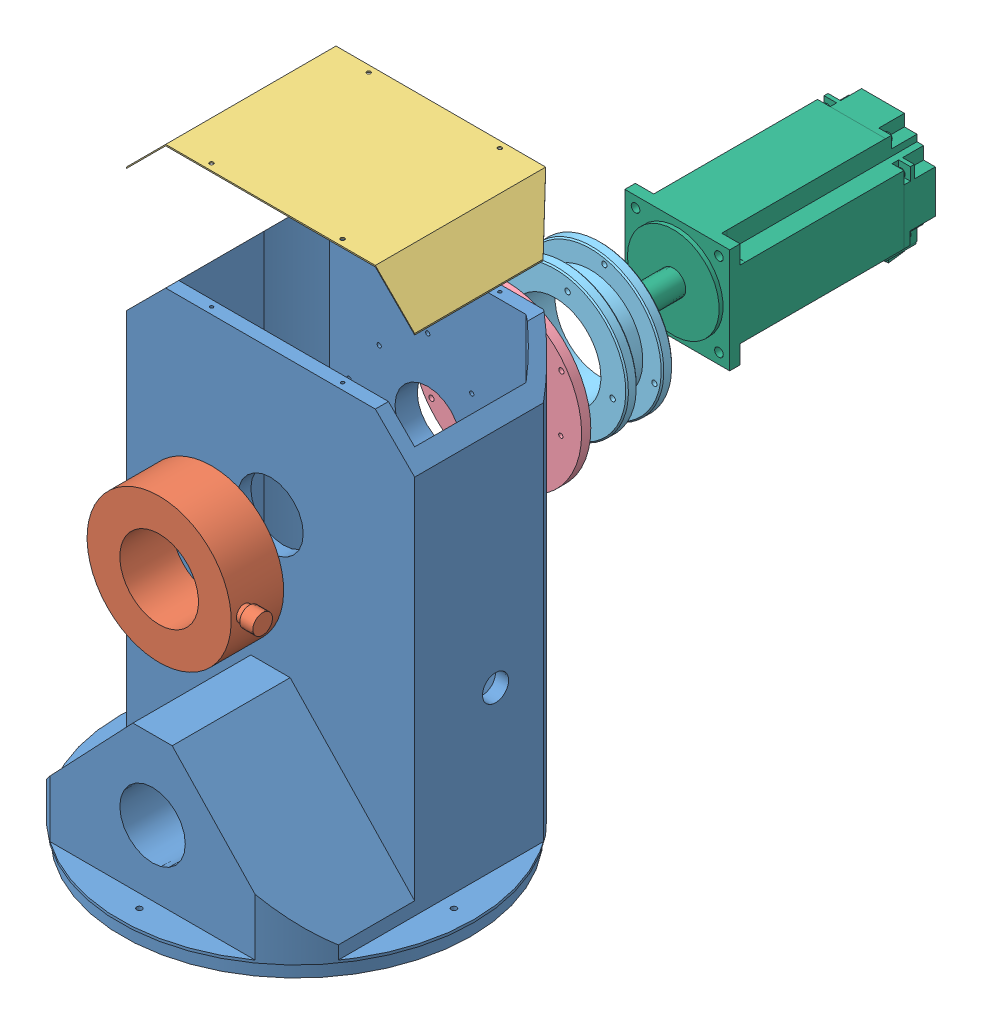
SolidWorks assembly Assem1, configuration Default. Lengths in mm.
Overall size (270 426.93 582.39).
6 component instances, 6 part files, 9 mates.
Components (placement in the parent):
- [K1]Thân.stp-1: [K1]Thân.stp [Default] at (187.1143 116.0959 260.3288) size (270 332 270)
- [K1]Vòng_Cản.stp-1: [K1]Vòng_Cản.stp [Default] at (187.1143 326.0959 365.2982) x (0 -1 0) z (1 0 0) size (110 40 124)
- [K1]Nắp_Đậy.stp-1: [K1]Nắp_Đậy.stp [Default] at (297.1143 500.0235 280.3288) x (-1 0 0) z (0 0 -1) size (220 31 130)
- [K1]Mặt_nối.stp-1: [K1]Mặt_nối.stp [Default] at (187.1143 326.0959 100.9008) x (0 0 1) z (-0.563414 0.826175 0) size (7 130 130)
- [K1]Mặt_Bích.stp-1: [K1]Mặt_Bích.stp [Default] at (187.1143 326.0959 63.2066) x (0.212845 0.977086 0) z (-0.977086 0.212845 0) size (110 35 110)
- [K1]Động_cơ.stp-1: [K1]Động_cơ.stp [Default] at (187.1143 326.0959 -30.0601) size (80 90.1 197)
Mates (geometry in assembly coordinates):
- Parallel1: parallel anti-aligned: plane of [K1]Thân.stp-1 through (187.1143 436.0959 215.3288) normal (0 1 0); plane of [K1]Nắp_Đậy.stp-1 through (267.1143 530.0235 280.3288) normal (0 -1 0)
- Parallel3: parallel aligned: plane of [K1]Thân.stp-1 through (77.1143 406.0959 150.3288) normal (-0.707107 0.707107 0); plane of [K1]Nắp_Đậy.stp-1 through (107.1143 531.0235 280.3288) normal (-0.707107 0.707107 0)
- Concentric2: concentric aligned: cylinder of [K1]Thân.stp-1 through (137.1143 432.0959 275.3288) axis (0 1 0) radius 1.2295; cylinder of [K1]Nắp_Đậy.stp-1 through (137.1143 527.0235 275.3288) axis (0 1 0) radius 1.5
- Concentric3: concentric anti-aligned: cylinder of [K1]Thân.stp-1 through (187.1143 326.0959 150.3288) axis (0 0 -1) radius 65; cylinder of [K1]Mặt_Bích.stp-1 through (187.1143 326.0959 59.2066) axis (0 0 1) radius 55
- Concentric5: concentric aligned: cylinder of [K1]Mặt_Bích.stp-1 through (187.1143 326.0959 45.7066) axis (0 0 1) radius 35; cylinder of [K1]Động_cơ.stp-1 through (187.1143 326.0959 -8.5601) axis (0 0 1) radius 9.5
- Parallel4: parallel aligned: plane of [K1]Thân.stp-1 through (187.1143 436.0959 215.3288) normal (0 1 0); plane of [K1]Động_cơ.stp-1 through (187.1143 366.0959 -96.5601) normal (0 1 0)
- Concentric6: concentric anti-aligned: cylinder of [K1]Thân.stp-1 through (187.1143 326.0959 -219.155) axis (0 0 1) radius 25; cylinder of [K1]Vòng_Cản.stp-1 through (187.1143 326.0959 495.8151) axis (0 0 -1) radius 30
- Parallel5: parallel aligned: plane of [K1]Thân.stp-1 through (297.1143 116.0959 280.3288) normal (1 0 0); plane of [K1]Vòng_Cản.stp-1 through (256.1143 326.0959 355.2982) normal (1 0 0)
- Concentric7: concentric anti-aligned: cylinder of [K1]Thân.stp-1 through (187.1143 326.0959 150.3288) axis (0 0 -1) radius 65; cylinder of [K1]Mặt_nối.stp-1 through (187.1143 326.0959 100.9008) axis (0 0 1) radius 65
